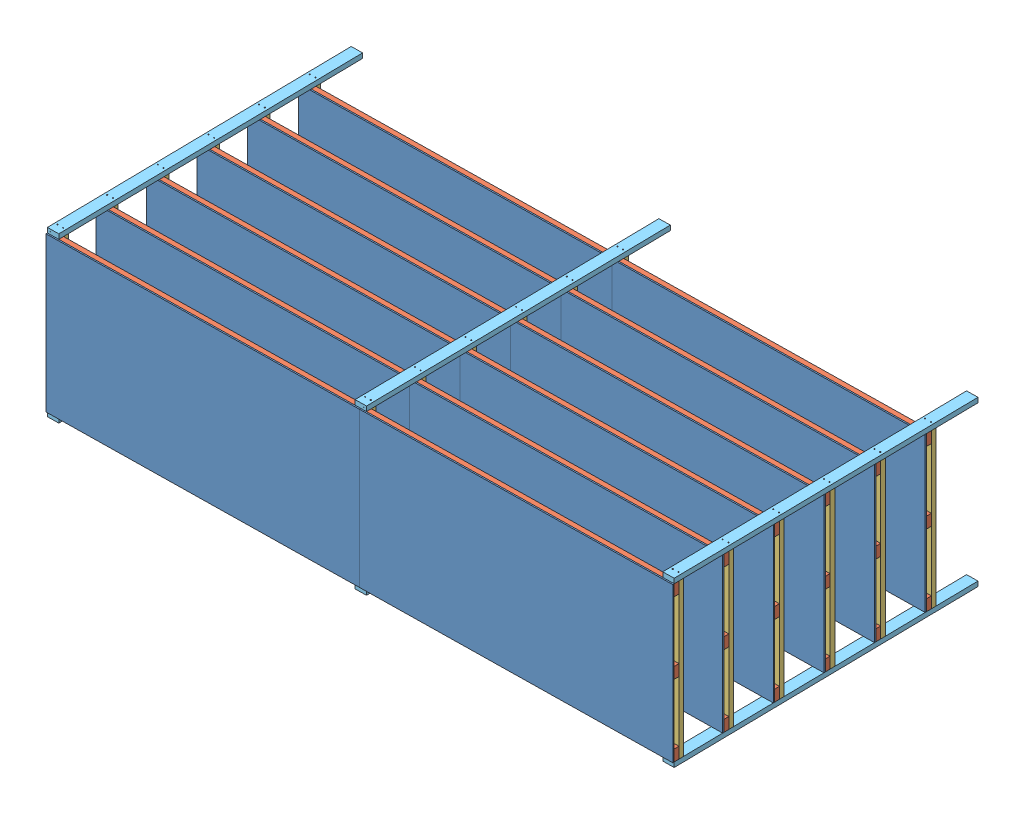
SolidWorks assembly Shelves, configuration Default. Lengths in mm.
Overall size (4914.37 1300.4 2525.2).
264 component instances, 5 part files, 8 mates.
Components (placement in the parent):
- Shelf-8: Shelf [Default] at (-1320.3436 -2276.2695 -924.1051) x (0 1 0) z (0.01558 0 0.999879) size (1219.2 4876.8 89.81)
  - Plywood_7-16X4ftX8ft-1: Plywood_7-16X4ftX8ft [Default] at (-1214.3269 -1248.9803 333.7822) size (1219.2 2438.4 11.11)
  - Plywood_7-16X4ftX8ft-2: Plywood_7-16X4ftX8ft [Default] at (-1214.3269 1189.4197 333.7822) size (1219.2 2438.4 11.11)
  - 2x4x16ft-4: 2x4x16ft [Default] at (-84.0269 -1248.9803 333.7822) x (1 0 0) z (0 1 0) size (88.9 38.1 4876.8)
  - 2x4x16ft-5: 2x4x16ft [Default] at (-649.1769 -1248.9803 333.7822) x (1 0 0) z (0 1 0) size (88.9 38.1 4876.8)
  - 2x4x16ft-6: 2x4x16ft [Default] at (-1214.3269 -1248.9803 333.7822) x (1 0 0) z (0 1 0) size (88.9 38.1 4876.8)
  - Fastened2x4x4ft-1: Fastened2x4x4ft [Default] at (-567.3467 -1138.8169 272.6519) x (0 1 0) z (-1 0 0) size (88.9 72.35 1219.2)
    - 2x4x4ft-1: 2x4x4ft [Default] at (-110.1634 -23.0303 -572.2198) size (88.9 38.1 1219.2)
    - DrywallScrew-1: DrywallScrew [Default] at (-65.7134 15.0697 624.7552) x (1 0 0) z (0 -1 0) size (6.35 6.35 72.35)
    - DrywallScrew-2: DrywallScrew [Default] at (-65.7134 15.0697 580.3052) x (1 0 0) z (0 -1 0) size (6.35 6.35 72.35)
    - DrywallScrew-3: DrywallScrew [Default] at (-65.7134 15.0697 59.6052) x (1 0 0) z (0 -1 0) size (6.35 6.35 72.35)
    - DrywallScrew-4: DrywallScrew [Default] at (-65.7134 15.0697 15.1552) x (1 0 0) z (0 -1 0) size (6.35 6.35 72.35)
    - DrywallScrew-5: DrywallScrew [Default] at (-65.7134 15.0697 -549.9948) x (1 0 0) z (0 -1 0) size (6.35 6.35 72.35)
    - DrywallScrew-6: DrywallScrew [Default] at (-65.7134 15.0697 -505.5448) x (1 0 0) z (0 -1 0) size (6.35 6.35 72.35)
  - Fastened2x4x4ft-2: Fastened2x4x4ft [Default] at (-567.3467 1255.1331 272.6519) x (0 1 0) z (-1 0 0) size (88.9 72.35 1219.2)
    - 2x4x4ft-1: 2x4x4ft [Default] at (-110.1634 -23.0303 -572.2198) size (88.9 38.1 1219.2)
    - DrywallScrew-1: DrywallScrew [Default] at (-65.7134 15.0697 624.7552) x (1 0 0) z (0 -1 0) size (6.35 6.35 72.35)
    - DrywallScrew-2: DrywallScrew [Default] at (-65.7134 15.0697 580.3052) x (1 0 0) z (0 -1 0) size (6.35 6.35 72.35)
    - DrywallScrew-3: DrywallScrew [Default] at (-65.7134 15.0697 59.6052) x (1 0 0) z (0 -1 0) size (6.35 6.35 72.35)
    - DrywallScrew-4: DrywallScrew [Default] at (-65.7134 15.0697 15.1552) x (1 0 0) z (0 -1 0) size (6.35 6.35 72.35)
    - DrywallScrew-5: DrywallScrew [Default] at (-65.7134 15.0697 -549.9948) x (1 0 0) z (0 -1 0) size (6.35 6.35 72.35)
    - DrywallScrew-6: DrywallScrew [Default] at (-65.7134 15.0697 -505.5448) x (1 0 0) z (0 -1 0) size (6.35 6.35 72.35)
  - Fastened2x4x4ft-3: Fastened2x4x4ft [Default] at (-642.1071 3517.6563 272.6519) x (0 -1 0) z (1 0 0) size (88.9 72.35 1219.2)
    - 2x4x4ft-1: 2x4x4ft [Default] at (-110.1634 -23.0303 -572.2198) size (88.9 38.1 1219.2)
    - DrywallScrew-1: DrywallScrew [Default] at (-65.7134 15.0697 624.7552) x (1 0 0) z (0 -1 0) size (6.35 6.35 72.35)
    - DrywallScrew-2: DrywallScrew [Default] at (-65.7134 15.0697 580.3052) x (1 0 0) z (0 -1 0) size (6.35 6.35 72.35)
    - DrywallScrew-3: DrywallScrew [Default] at (-65.7134 15.0697 59.6052) x (1 0 0) z (0 -1 0) size (6.35 6.35 72.35)
    - DrywallScrew-4: DrywallScrew [Default] at (-65.7134 15.0697 15.1552) x (1 0 0) z (0 -1 0) size (6.35 6.35 72.35)
    - DrywallScrew-5: DrywallScrew [Default] at (-65.7134 15.0697 -549.9948) x (1 0 0) z (0 -1 0) size (6.35 6.35 72.35)
    - DrywallScrew-6: DrywallScrew [Default] at (-65.7134 15.0697 -505.5448) x (1 0 0) z (0 -1 0) size (6.35 6.35 72.35)
- Fastened2x4x8ft-1: Fastened2x4x8ft [Default] at (199.4493 -2217.0742 10.0157) x (0.999879 0 -0.01558) z (0.01558 0 0.999879) size (88.9 72.35 2438.4)
  - 2x4x8ft-1: 2x4x8ft [Default] at (-344.9743 -54.3222 -1036.654) size (88.9 38.1 2438.4)
  - DrywallScrew-1: DrywallScrew [Default] at (-322.7493 -16.2222 1344.596) x (1 0 0) z (0 -1 0) size (6.35 6.35 72.35)
  - DrywallScrew-2: DrywallScrew [Default] at (-278.2993 -16.2222 1344.596) x (1 0 0) z (0 -1 0) size (6.35 6.35 72.35)
  - DrywallScrew-3: DrywallScrew [Default] at (-278.2993 -16.2222 944.546) x (1 0 0) z (0 -1 0) size (6.35 6.35 72.35)
  - DrywallScrew-4: DrywallScrew [Default] at (-322.7493 -16.2222 944.546) x (1 0 0) z (0 -1 0) size (6.35 6.35 72.35)
  - DrywallScrew-5: DrywallScrew [Default] at (-278.2993 -16.2222 538.146) x (1 0 0) z (0 -1 0) size (6.35 6.35 72.35)
  - DrywallScrew-6: DrywallScrew [Default] at (-278.2993 -16.2222 131.746) x (1 0 0) z (0 -1 0) size (6.35 6.35 72.35)
  - DrywallScrew-7: DrywallScrew [Default] at (-278.2993 -16.2222 -274.654) x (1 0 0) z (0 -1 0) size (6.35 6.35 72.35)
  - DrywallScrew-8: DrywallScrew [Default] at (-278.2993 -16.2222 -681.054) x (1 0 0) z (0 -1 0) size (6.35 6.35 72.35)
  - DrywallScrew-9: DrywallScrew [Default] at (-322.7493 -16.2222 538.146) x (1 0 0) z (0 -1 0) size (6.35 6.35 72.35)
  - DrywallScrew-10: DrywallScrew [Default] at (-322.7493 -16.2222 131.746) x (1 0 0) z (0 -1 0) size (6.35 6.35 72.35)
  - DrywallScrew-11: DrywallScrew [Default] at (-322.7493 -16.2222 -274.654) x (1 0 0) z (0 -1 0) size (6.35 6.35 72.35)
  - DrywallScrew-12: DrywallScrew [Default] at (-322.7493 -16.2222 -681.054) x (1 0 0) z (0 -1 0) size (6.35 6.35 72.35)
- Fastened2x4x8ft-2: Fastened2x4x8ft [Default] at (-4587.8696 -2217.0742 84.6123) x (0.999879 0 -0.01558) z (0.01558 0 0.999879) size (88.9 72.35 2438.4)
  - 2x4x8ft-1: 2x4x8ft [Default] at (-344.9743 -54.3222 -1036.654) size (88.9 38.1 2438.4)
  - DrywallScrew-1: DrywallScrew [Default] at (-322.7493 -16.2222 1344.596) x (1 0 0) z (0 -1 0) size (6.35 6.35 72.35)
  - DrywallScrew-2: DrywallScrew [Default] at (-278.2993 -16.2222 1344.596) x (1 0 0) z (0 -1 0) size (6.35 6.35 72.35)
  - DrywallScrew-3: DrywallScrew [Default] at (-278.2993 -16.2222 944.546) x (1 0 0) z (0 -1 0) size (6.35 6.35 72.35)
  - DrywallScrew-4: DrywallScrew [Default] at (-322.7493 -16.2222 944.546) x (1 0 0) z (0 -1 0) size (6.35 6.35 72.35)
  - DrywallScrew-5: DrywallScrew [Default] at (-278.2993 -16.2222 538.146) x (1 0 0) z (0 -1 0) size (6.35 6.35 72.35)
  - DrywallScrew-6: DrywallScrew [Default] at (-278.2993 -16.2222 131.746) x (1 0 0) z (0 -1 0) size (6.35 6.35 72.35)
  - DrywallScrew-7: DrywallScrew [Default] at (-278.2993 -16.2222 -274.654) x (1 0 0) z (0 -1 0) size (6.35 6.35 72.35)
  - DrywallScrew-8: DrywallScrew [Default] at (-278.2993 -16.2222 -681.054) x (1 0 0) z (0 -1 0) size (6.35 6.35 72.35)
  - DrywallScrew-9: DrywallScrew [Default] at (-322.7493 -16.2222 538.146) x (1 0 0) z (0 -1 0) size (6.35 6.35 72.35)
  - DrywallScrew-10: DrywallScrew [Default] at (-322.7493 -16.2222 131.746) x (1 0 0) z (0 -1 0) size (6.35 6.35 72.35)
  - DrywallScrew-11: DrywallScrew [Default] at (-322.7493 -16.2222 -274.654) x (1 0 0) z (0 -1 0) size (6.35 6.35 72.35)
  - DrywallScrew-12: DrywallScrew [Default] at (-322.7493 -16.2222 -681.054) x (1 0 0) z (0 -1 0) size (6.35 6.35 72.35)
- Fastened2x4x8ft-3: Fastened2x4x8ft [Default] at (-2194.2102 -2217.0742 47.314) x (0.999879 0 -0.01558) z (0.01558 0 0.999879) size (88.9 72.35 2438.4)
  - 2x4x8ft-1: 2x4x8ft [Default] at (-344.9743 -54.3222 -1036.654) size (88.9 38.1 2438.4)
  - DrywallScrew-1: DrywallScrew [Default] at (-322.7493 -16.2222 1344.596) x (1 0 0) z (0 -1 0) size (6.35 6.35 72.35)
  - DrywallScrew-2: DrywallScrew [Default] at (-278.2993 -16.2222 1344.596) x (1 0 0) z (0 -1 0) size (6.35 6.35 72.35)
  - DrywallScrew-3: DrywallScrew [Default] at (-278.2993 -16.2222 944.546) x (1 0 0) z (0 -1 0) size (6.35 6.35 72.35)
  - DrywallScrew-4: DrywallScrew [Default] at (-322.7493 -16.2222 944.546) x (1 0 0) z (0 -1 0) size (6.35 6.35 72.35)
  - DrywallScrew-5: DrywallScrew [Default] at (-278.2993 -16.2222 538.146) x (1 0 0) z (0 -1 0) size (6.35 6.35 72.35)
  - DrywallScrew-6: DrywallScrew [Default] at (-278.2993 -16.2222 131.746) x (1 0 0) z (0 -1 0) size (6.35 6.35 72.35)
  - DrywallScrew-7: DrywallScrew [Default] at (-278.2993 -16.2222 -274.654) x (1 0 0) z (0 -1 0) size (6.35 6.35 72.35)
  - DrywallScrew-8: DrywallScrew [Default] at (-278.2993 -16.2222 -681.054) x (1 0 0) z (0 -1 0) size (6.35 6.35 72.35)
  - DrywallScrew-9: DrywallScrew [Default] at (-322.7493 -16.2222 538.146) x (1 0 0) z (0 -1 0) size (6.35 6.35 72.35)
  - DrywallScrew-10: DrywallScrew [Default] at (-322.7493 -16.2222 131.746) x (1 0 0) z (0 -1 0) size (6.35 6.35 72.35)
  - DrywallScrew-11: DrywallScrew [Default] at (-322.7493 -16.2222 -274.654) x (1 0 0) z (0 -1 0) size (6.35 6.35 72.35)
  - DrywallScrew-12: DrywallScrew [Default] at (-322.7493 -16.2222 -681.054) x (1 0 0) z (0 -1 0) size (6.35 6.35 72.35)
- Fastened2x4x8ft-4: Fastened2x4x8ft [Default] at (-2795.1858 -3544.9185 56.6785) x (-0.999879 0 0.01558) z (0.01558 0 0.999879) size (88.9 72.35 2438.4)
  - 2x4x8ft-1: 2x4x8ft [Default] at (-344.9743 -54.3222 -1036.654) size (88.9 38.1 2438.4)
  - DrywallScrew-1: DrywallScrew [Default] at (-322.7493 -16.2222 1344.596) x (1 0 0) z (0 -1 0) size (6.35 6.35 72.35)
  - DrywallScrew-2: DrywallScrew [Default] at (-278.2993 -16.2222 1344.596) x (1 0 0) z (0 -1 0) size (6.35 6.35 72.35)
  - DrywallScrew-3: DrywallScrew [Default] at (-278.2993 -16.2222 944.546) x (1 0 0) z (0 -1 0) size (6.35 6.35 72.35)
  - DrywallScrew-4: DrywallScrew [Default] at (-322.7493 -16.2222 944.546) x (1 0 0) z (0 -1 0) size (6.35 6.35 72.35)
  - DrywallScrew-5: DrywallScrew [Default] at (-278.2993 -16.2222 538.146) x (1 0 0) z (0 -1 0) size (6.35 6.35 72.35)
  - DrywallScrew-6: DrywallScrew [Default] at (-278.2993 -16.2222 131.746) x (1 0 0) z (0 -1 0) size (6.35 6.35 72.35)
  - DrywallScrew-7: DrywallScrew [Default] at (-278.2993 -16.2222 -274.654) x (1 0 0) z (0 -1 0) size (6.35 6.35 72.35)
  - DrywallScrew-8: DrywallScrew [Default] at (-278.2993 -16.2222 -681.054) x (1 0 0) z (0 -1 0) size (6.35 6.35 72.35)
  - DrywallScrew-9: DrywallScrew [Default] at (-322.7493 -16.2222 538.146) x (1 0 0) z (0 -1 0) size (6.35 6.35 72.35)
  - DrywallScrew-10: DrywallScrew [Default] at (-322.7493 -16.2222 131.746) x (1 0 0) z (0 -1 0) size (6.35 6.35 72.35)
  - DrywallScrew-11: DrywallScrew [Default] at (-322.7493 -16.2222 -274.654) x (1 0 0) z (0 -1 0) size (6.35 6.35 72.35)
  - DrywallScrew-12: DrywallScrew [Default] at (-322.7493 -16.2222 -681.054) x (1 0 0) z (0 -1 0) size (6.35 6.35 72.35)
- Fastened2x4x8ft-5: Fastened2x4x8ft [Default] at (-5188.8453 -3544.9185 93.9768) x (-0.999879 0 0.01558) z (0.01558 0 0.999879) size (88.9 72.35 2438.4)
  - 2x4x8ft-1: 2x4x8ft [Default] at (-344.9743 -54.3222 -1036.654) size (88.9 38.1 2438.4)
  - DrywallScrew-1: DrywallScrew [Default] at (-322.7493 -16.2222 1344.596) x (1 0 0) z (0 -1 0) size (6.35 6.35 72.35)
  - DrywallScrew-2: DrywallScrew [Default] at (-278.2993 -16.2222 1344.596) x (1 0 0) z (0 -1 0) size (6.35 6.35 72.35)
  - DrywallScrew-3: DrywallScrew [Default] at (-278.2993 -16.2222 944.546) x (1 0 0) z (0 -1 0) size (6.35 6.35 72.35)
  - DrywallScrew-4: DrywallScrew [Default] at (-322.7493 -16.2222 944.546) x (1 0 0) z (0 -1 0) size (6.35 6.35 72.35)
  - DrywallScrew-5: DrywallScrew [Default] at (-278.2993 -16.2222 538.146) x (1 0 0) z (0 -1 0) size (6.35 6.35 72.35)
  - DrywallScrew-6: DrywallScrew [Default] at (-278.2993 -16.2222 131.746) x (1 0 0) z (0 -1 0) size (6.35 6.35 72.35)
  - DrywallScrew-7: DrywallScrew [Default] at (-278.2993 -16.2222 -274.654) x (1 0 0) z (0 -1 0) size (6.35 6.35 72.35)
  - DrywallScrew-8: DrywallScrew [Default] at (-278.2993 -16.2222 -681.054) x (1 0 0) z (0 -1 0) size (6.35 6.35 72.35)
  - DrywallScrew-9: DrywallScrew [Default] at (-322.7493 -16.2222 538.146) x (1 0 0) z (0 -1 0) size (6.35 6.35 72.35)
  - DrywallScrew-10: DrywallScrew [Default] at (-322.7493 -16.2222 131.746) x (1 0 0) z (0 -1 0) size (6.35 6.35 72.35)
  - DrywallScrew-11: DrywallScrew [Default] at (-322.7493 -16.2222 -274.654) x (1 0 0) z (0 -1 0) size (6.35 6.35 72.35)
  - DrywallScrew-12: DrywallScrew [Default] at (-322.7493 -16.2222 -681.054) x (1 0 0) z (0 -1 0) size (6.35 6.35 72.35)
- Fastened2x4x8ft-6: Fastened2x4x8ft [Default] at (-401.5264 -3544.9185 19.3802) x (-0.999879 0 0.01558) z (0.01558 0 0.999879) size (88.9 72.35 2438.4)
  - 2x4x8ft-1: 2x4x8ft [Default] at (-344.9743 -54.3222 -1036.654) size (88.9 38.1 2438.4)
  - DrywallScrew-1: DrywallScrew [Default] at (-322.7493 -16.2222 1344.596) x (1 0 0) z (0 -1 0) size (6.35 6.35 72.35)
  - DrywallScrew-2: DrywallScrew [Default] at (-278.2993 -16.2222 1344.596) x (1 0 0) z (0 -1 0) size (6.35 6.35 72.35)
  - DrywallScrew-3: DrywallScrew [Default] at (-278.2993 -16.2222 944.546) x (1 0 0) z (0 -1 0) size (6.35 6.35 72.35)
  - DrywallScrew-4: DrywallScrew [Default] at (-322.7493 -16.2222 944.546) x (1 0 0) z (0 -1 0) size (6.35 6.35 72.35)
  - DrywallScrew-5: DrywallScrew [Default] at (-278.2993 -16.2222 538.146) x (1 0 0) z (0 -1 0) size (6.35 6.35 72.35)
  - DrywallScrew-6: DrywallScrew [Default] at (-278.2993 -16.2222 131.746) x (1 0 0) z (0 -1 0) size (6.35 6.35 72.35)
  - DrywallScrew-7: DrywallScrew [Default] at (-278.2993 -16.2222 -274.654) x (1 0 0) z (0 -1 0) size (6.35 6.35 72.35)
  - DrywallScrew-8: DrywallScrew [Default] at (-278.2993 -16.2222 -681.054) x (1 0 0) z (0 -1 0) size (6.35 6.35 72.35)
  - DrywallScrew-9: DrywallScrew [Default] at (-322.7493 -16.2222 538.146) x (1 0 0) z (0 -1 0) size (6.35 6.35 72.35)
  - DrywallScrew-10: DrywallScrew [Default] at (-322.7493 -16.2222 131.746) x (1 0 0) z (0 -1 0) size (6.35 6.35 72.35)
  - DrywallScrew-11: DrywallScrew [Default] at (-322.7493 -16.2222 -274.654) x (1 0 0) z (0 -1 0) size (6.35 6.35 72.35)
  - DrywallScrew-12: DrywallScrew [Default] at (-322.7493 -16.2222 -681.054) x (1 0 0) z (0 -1 0) size (6.35 6.35 72.35)
- Shelf-9: Shelf [Default] at (-1314.0118 -2276.2695 -517.7545) x (0 1 0) z (0.01558 0 0.999879) size (1219.2 4876.8 89.81)
  - Plywood_7-16X4ftX8ft-1: Plywood_7-16X4ftX8ft [Default] at (-1214.3269 -1248.9803 333.7822) size (1219.2 2438.4 11.11)
  - Plywood_7-16X4ftX8ft-2: Plywood_7-16X4ftX8ft [Default] at (-1214.3269 1189.4197 333.7822) size (1219.2 2438.4 11.11)
  - 2x4x16ft-4: 2x4x16ft [Default] at (-84.0269 -1248.9803 333.7822) x (1 0 0) z (0 1 0) size (88.9 38.1 4876.8)
  - 2x4x16ft-5: 2x4x16ft [Default] at (-649.1769 -1248.9803 333.7822) x (1 0 0) z (0 1 0) size (88.9 38.1 4876.8)
  - 2x4x16ft-6: 2x4x16ft [Default] at (-1214.3269 -1248.9803 333.7822) x (1 0 0) z (0 1 0) size (88.9 38.1 4876.8)
  - Fastened2x4x4ft-1: Fastened2x4x4ft [Default] at (-567.3467 -1138.8169 272.6519) x (0 1 0) z (-1 0 0) size (88.9 72.35 1219.2)
    - 2x4x4ft-1: 2x4x4ft [Default] at (-110.1634 -23.0303 -572.2198) size (88.9 38.1 1219.2)
    - DrywallScrew-1: DrywallScrew [Default] at (-65.7134 15.0697 624.7552) x (1 0 0) z (0 -1 0) size (6.35 6.35 72.35)
    - DrywallScrew-2: DrywallScrew [Default] at (-65.7134 15.0697 580.3052) x (1 0 0) z (0 -1 0) size (6.35 6.35 72.35)
    - DrywallScrew-3: DrywallScrew [Default] at (-65.7134 15.0697 59.6052) x (1 0 0) z (0 -1 0) size (6.35 6.35 72.35)
    - DrywallScrew-4: DrywallScrew [Default] at (-65.7134 15.0697 15.1552) x (1 0 0) z (0 -1 0) size (6.35 6.35 72.35)
    - DrywallScrew-5: DrywallScrew [Default] at (-65.7134 15.0697 -549.9948) x (1 0 0) z (0 -1 0) size (6.35 6.35 72.35)
    - DrywallScrew-6: DrywallScrew [Default] at (-65.7134 15.0697 -505.5448) x (1 0 0) z (0 -1 0) size (6.35 6.35 72.35)
  - Fastened2x4x4ft-2: Fastened2x4x4ft [Default] at (-567.3467 1255.1331 272.6519) x (0 1 0) z (-1 0 0) size (88.9 72.35 1219.2)
    - 2x4x4ft-1: 2x4x4ft [Default] at (-110.1634 -23.0303 -572.2198) size (88.9 38.1 1219.2)
    - DrywallScrew-1: DrywallScrew [Default] at (-65.7134 15.0697 624.7552) x (1 0 0) z (0 -1 0) size (6.35 6.35 72.35)
    - DrywallScrew-2: DrywallScrew [Default] at (-65.7134 15.0697 580.3052) x (1 0 0) z (0 -1 0) size (6.35 6.35 72.35)
    - DrywallScrew-3: DrywallScrew [Default] at (-65.7134 15.0697 59.6052) x (1 0 0) z (0 -1 0) size (6.35 6.35 72.35)
    - DrywallScrew-4: DrywallScrew [Default] at (-65.7134 15.0697 15.1552) x (1 0 0) z (0 -1 0) size (6.35 6.35 72.35)
    - DrywallScrew-5: DrywallScrew [Default] at (-65.7134 15.0697 -549.9948) x (1 0 0) z (0 -1 0) size (6.35 6.35 72.35)
    - DrywallScrew-6: DrywallScrew [Default] at (-65.7134 15.0697 -505.5448) x (1 0 0) z (0 -1 0) size (6.35 6.35 72.35)
  - Fastened2x4x4ft-3: Fastened2x4x4ft [Default] at (-642.1071 3517.6563 272.6519) x (0 -1 0) z (1 0 0) size (88.9 72.35 1219.2)
    - 2x4x4ft-1: 2x4x4ft [Default] at (-110.1634 -23.0303 -572.2198) size (88.9 38.1 1219.2)
    - DrywallScrew-1: DrywallScrew [Default] at (-65.7134 15.0697 624.7552) x (1 0 0) z (0 -1 0) size (6.35 6.35 72.35)
    - DrywallScrew-2: DrywallScrew [Default] at (-65.7134 15.0697 580.3052) x (1 0 0) z (0 -1 0) size (6.35 6.35 72.35)
    - DrywallScrew-3: DrywallScrew [Default] at (-65.7134 15.0697 59.6052) x (1 0 0) z (0 -1 0) size (6.35 6.35 72.35)
    - DrywallScrew-4: DrywallScrew [Default] at (-65.7134 15.0697 15.1552) x (1 0 0) z (0 -1 0) size (6.35 6.35 72.35)
    - DrywallScrew-5: DrywallScrew [Default] at (-65.7134 15.0697 -549.9948) x (1 0 0) z (0 -1 0) size (6.35 6.35 72.35)
    - DrywallScrew-6: DrywallScrew [Default] at (-65.7134 15.0697 -505.5448) x (1 0 0) z (0 -1 0) size (6.35 6.35 72.35)
- Shelf-10: Shelf [Default] at (-1307.68 -2276.2695 -111.4038) x (0 1 0) z (0.01558 0 0.999879) size (1219.2 4876.8 89.81)
  - Plywood_7-16X4ftX8ft-1: Plywood_7-16X4ftX8ft [Default] at (-1214.3269 -1248.9803 333.7822) size (1219.2 2438.4 11.11)
  - Plywood_7-16X4ftX8ft-2: Plywood_7-16X4ftX8ft [Default] at (-1214.3269 1189.4197 333.7822) size (1219.2 2438.4 11.11)
  - 2x4x16ft-4: 2x4x16ft [Default] at (-84.0269 -1248.9803 333.7822) x (1 0 0) z (0 1 0) size (88.9 38.1 4876.8)
  - 2x4x16ft-5: 2x4x16ft [Default] at (-649.1769 -1248.9803 333.7822) x (1 0 0) z (0 1 0) size (88.9 38.1 4876.8)
  - 2x4x16ft-6: 2x4x16ft [Default] at (-1214.3269 -1248.9803 333.7822) x (1 0 0) z (0 1 0) size (88.9 38.1 4876.8)
  - Fastened2x4x4ft-1: Fastened2x4x4ft [Default] at (-567.3467 -1138.8169 272.6519) x (0 1 0) z (-1 0 0) size (88.9 72.35 1219.2)
    - 2x4x4ft-1: 2x4x4ft [Default] at (-110.1634 -23.0303 -572.2198) size (88.9 38.1 1219.2)
    - DrywallScrew-1: DrywallScrew [Default] at (-65.7134 15.0697 624.7552) x (1 0 0) z (0 -1 0) size (6.35 6.35 72.35)
    - DrywallScrew-2: DrywallScrew [Default] at (-65.7134 15.0697 580.3052) x (1 0 0) z (0 -1 0) size (6.35 6.35 72.35)
    - DrywallScrew-3: DrywallScrew [Default] at (-65.7134 15.0697 59.6052) x (1 0 0) z (0 -1 0) size (6.35 6.35 72.35)
    - DrywallScrew-4: DrywallScrew [Default] at (-65.7134 15.0697 15.1552) x (1 0 0) z (0 -1 0) size (6.35 6.35 72.35)
    - DrywallScrew-5: DrywallScrew [Default] at (-65.7134 15.0697 -549.9948) x (1 0 0) z (0 -1 0) size (6.35 6.35 72.35)
    - DrywallScrew-6: DrywallScrew [Default] at (-65.7134 15.0697 -505.5448) x (1 0 0) z (0 -1 0) size (6.35 6.35 72.35)
  - Fastened2x4x4ft-2: Fastened2x4x4ft [Default] at (-567.3467 1255.1331 272.6519) x (0 1 0) z (-1 0 0) size (88.9 72.35 1219.2)
    - 2x4x4ft-1: 2x4x4ft [Default] at (-110.1634 -23.0303 -572.2198) size (88.9 38.1 1219.2)
    - DrywallScrew-1: DrywallScrew [Default] at (-65.7134 15.0697 624.7552) x (1 0 0) z (0 -1 0) size (6.35 6.35 72.35)
    - DrywallScrew-2: DrywallScrew [Default] at (-65.7134 15.0697 580.3052) x (1 0 0) z (0 -1 0) size (6.35 6.35 72.35)
    - DrywallScrew-3: DrywallScrew [Default] at (-65.7134 15.0697 59.6052) x (1 0 0) z (0 -1 0) size (6.35 6.35 72.35)
    - DrywallScrew-4: DrywallScrew [Default] at (-65.7134 15.0697 15.1552) x (1 0 0) z (0 -1 0) size (6.35 6.35 72.35)
    - DrywallScrew-5: DrywallScrew [Default] at (-65.7134 15.0697 -549.9948) x (1 0 0) z (0 -1 0) size (6.35 6.35 72.35)
    - DrywallScrew-6: DrywallScrew [Default] at (-65.7134 15.0697 -505.5448) x (1 0 0) z (0 -1 0) size (6.35 6.35 72.35)
  - Fastened2x4x4ft-3: Fastened2x4x4ft [Default] at (-642.1071 3517.6563 272.6519) x (0 -1 0) z (1 0 0) size (88.9 72.35 1219.2)
    - 2x4x4ft-1: 2x4x4ft [Default] at (-110.1634 -23.0303 -572.2198) size (88.9 38.1 1219.2)
    - DrywallScrew-1: DrywallScrew [Default] at (-65.7134 15.0697 624.7552) x (1 0 0) z (0 -1 0) size (6.35 6.35 72.35)
    - DrywallScrew-2: DrywallScrew [Default] at (-65.7134 15.0697 580.3052) x (1 0 0) z (0 -1 0) size (6.35 6.35 72.35)
    - DrywallScrew-3: DrywallScrew [Default] at (-65.7134 15.0697 59.6052) x (1 0 0) z (0 -1 0) size (6.35 6.35 72.35)
    - DrywallScrew-4: DrywallScrew [Default] at (-65.7134 15.0697 15.1552) x (1 0 0) z (0 -1 0) size (6.35 6.35 72.35)
    - DrywallScrew-5: DrywallScrew [Default] at (-65.7134 15.0697 -549.9948) x (1 0 0) z (0 -1 0) size (6.35 6.35 72.35)
    - DrywallScrew-6: DrywallScrew [Default] at (-65.7134 15.0697 -505.5448) x (1 0 0) z (0 -1 0) size (6.35 6.35 72.35)
- Shelf-11: Shelf [Default] at (-1301.3482 -2276.2695 294.9469) x (0 1 0) z (0.01558 0 0.999879) size (1219.2 4876.8 89.81)
  - Plywood_7-16X4ftX8ft-1: Plywood_7-16X4ftX8ft [Default] at (-1214.3269 -1248.9803 333.7822) size (1219.2 2438.4 11.11)
  - Plywood_7-16X4ftX8ft-2: Plywood_7-16X4ftX8ft [Default] at (-1214.3269 1189.4197 333.7822) size (1219.2 2438.4 11.11)
  - 2x4x16ft-4: 2x4x16ft [Default] at (-84.0269 -1248.9803 333.7822) x (1 0 0) z (0 1 0) size (88.9 38.1 4876.8)
  - 2x4x16ft-5: 2x4x16ft [Default] at (-649.1769 -1248.9803 333.7822) x (1 0 0) z (0 1 0) size (88.9 38.1 4876.8)
  - 2x4x16ft-6: 2x4x16ft [Default] at (-1214.3269 -1248.9803 333.7822) x (1 0 0) z (0 1 0) size (88.9 38.1 4876.8)
  - Fastened2x4x4ft-1: Fastened2x4x4ft [Default] at (-567.3467 -1138.8169 272.6519) x (0 1 0) z (-1 0 0) size (88.9 72.35 1219.2)
    - 2x4x4ft-1: 2x4x4ft [Default] at (-110.1634 -23.0303 -572.2198) size (88.9 38.1 1219.2)
    - DrywallScrew-1: DrywallScrew [Default] at (-65.7134 15.0697 624.7552) x (1 0 0) z (0 -1 0) size (6.35 6.35 72.35)
    - DrywallScrew-2: DrywallScrew [Default] at (-65.7134 15.0697 580.3052) x (1 0 0) z (0 -1 0) size (6.35 6.35 72.35)
    - DrywallScrew-3: DrywallScrew [Default] at (-65.7134 15.0697 59.6052) x (1 0 0) z (0 -1 0) size (6.35 6.35 72.35)
    - DrywallScrew-4: DrywallScrew [Default] at (-65.7134 15.0697 15.1552) x (1 0 0) z (0 -1 0) size (6.35 6.35 72.35)
    - DrywallScrew-5: DrywallScrew [Default] at (-65.7134 15.0697 -549.9948) x (1 0 0) z (0 -1 0) size (6.35 6.35 72.35)
    - DrywallScrew-6: DrywallScrew [Default] at (-65.7134 15.0697 -505.5448) x (1 0 0) z (0 -1 0) size (6.35 6.35 72.35)
  - Fastened2x4x4ft-2: Fastened2x4x4ft [Default] at (-567.3467 1255.1331 272.6519) x (0 1 0) z (-1 0 0) size (88.9 72.35 1219.2)
    - 2x4x4ft-1: 2x4x4ft [Default] at (-110.1634 -23.0303 -572.2198) size (88.9 38.1 1219.2)
    - DrywallScrew-1: DrywallScrew [Default] at (-65.7134 15.0697 624.7552) x (1 0 0) z (0 -1 0) size (6.35 6.35 72.35)
    - DrywallScrew-2: DrywallScrew [Default] at (-65.7134 15.0697 580.3052) x (1 0 0) z (0 -1 0) size (6.35 6.35 72.35)
    - DrywallScrew-3: DrywallScrew [Default] at (-65.7134 15.0697 59.6052) x (1 0 0) z (0 -1 0) size (6.35 6.35 72.35)
    - DrywallScrew-4: DrywallScrew [Default] at (-65.7134 15.0697 15.1552) x (1 0 0) z (0 -1 0) size (6.35 6.35 72.35)
    - DrywallScrew-5: DrywallScrew [Default] at (-65.7134 15.0697 -549.9948) x (1 0 0) z (0 -1 0) size (6.35 6.35 72.35)
    - DrywallScrew-6: DrywallScrew [Default] at (-65.7134 15.0697 -505.5448) x (1 0 0) z (0 -1 0) size (6.35 6.35 72.35)
  - Fastened2x4x4ft-3: Fastened2x4x4ft [Default] at (-642.1071 3517.6563 272.6519) x (0 -1 0) z (1 0 0) size (88.9 72.35 1219.2)
    - 2x4x4ft-1: 2x4x4ft [Default] at (-110.1634 -23.0303 -572.2198) size (88.9 38.1 1219.2)
    - DrywallScrew-1: DrywallScrew [Default] at (-65.7134 15.0697 624.7552) x (1 0 0) z (0 -1 0) size (6.35 6.35 72.35)
    - DrywallScrew-2: DrywallScrew [Default] at (-65.7134 15.0697 580.3052) x (1 0 0) z (0 -1 0) size (6.35 6.35 72.35)
    - DrywallScrew-3: DrywallScrew [Default] at (-65.7134 15.0697 59.6052) x (1 0 0) z (0 -1 0) size (6.35 6.35 72.35)
    - DrywallScrew-4: DrywallScrew [Default] at (-65.7134 15.0697 15.1552) x (1 0 0) z (0 -1 0) size (6.35 6.35 72.35)
    - DrywallScrew-5: DrywallScrew [Default] at (-65.7134 15.0697 -549.9948) x (1 0 0) z (0 -1 0) size (6.35 6.35 72.35)
    - DrywallScrew-6: DrywallScrew [Default] at (-65.7134 15.0697 -505.5448) x (1 0 0) z (0 -1 0) size (6.35 6.35 72.35)
- Shelf-12: Shelf [Default] at (-1295.0164 -2276.2695 701.2976) x (0 1 0) z (0.01558 0 0.999879) size (1219.2 4876.8 89.81)
  - Plywood_7-16X4ftX8ft-1: Plywood_7-16X4ftX8ft [Default] at (-1214.3269 -1248.9803 333.7822) size (1219.2 2438.4 11.11)
  - Plywood_7-16X4ftX8ft-2: Plywood_7-16X4ftX8ft [Default] at (-1214.3269 1189.4197 333.7822) size (1219.2 2438.4 11.11)
  - 2x4x16ft-4: 2x4x16ft [Default] at (-84.0269 -1248.9803 333.7822) x (1 0 0) z (0 1 0) size (88.9 38.1 4876.8)
  - 2x4x16ft-5: 2x4x16ft [Default] at (-649.1769 -1248.9803 333.7822) x (1 0 0) z (0 1 0) size (88.9 38.1 4876.8)
  - 2x4x16ft-6: 2x4x16ft [Default] at (-1214.3269 -1248.9803 333.7822) x (1 0 0) z (0 1 0) size (88.9 38.1 4876.8)
  - Fastened2x4x4ft-1: Fastened2x4x4ft [Default] at (-567.3467 -1138.8169 272.6519) x (0 1 0) z (-1 0 0) size (88.9 72.35 1219.2)
    - 2x4x4ft-1: 2x4x4ft [Default] at (-110.1634 -23.0303 -572.2198) size (88.9 38.1 1219.2)
    - DrywallScrew-1: DrywallScrew [Default] at (-65.7134 15.0697 624.7552) x (1 0 0) z (0 -1 0) size (6.35 6.35 72.35)
    - DrywallScrew-2: DrywallScrew [Default] at (-65.7134 15.0697 580.3052) x (1 0 0) z (0 -1 0) size (6.35 6.35 72.35)
    - DrywallScrew-3: DrywallScrew [Default] at (-65.7134 15.0697 59.6052) x (1 0 0) z (0 -1 0) size (6.35 6.35 72.35)
    - DrywallScrew-4: DrywallScrew [Default] at (-65.7134 15.0697 15.1552) x (1 0 0) z (0 -1 0) size (6.35 6.35 72.35)
    - DrywallScrew-5: DrywallScrew [Default] at (-65.7134 15.0697 -549.9948) x (1 0 0) z (0 -1 0) size (6.35 6.35 72.35)
    - DrywallScrew-6: DrywallScrew [Default] at (-65.7134 15.0697 -505.5448) x (1 0 0) z (0 -1 0) size (6.35 6.35 72.35)
  - Fastened2x4x4ft-2: Fastened2x4x4ft [Default] at (-567.3467 1255.1331 272.6519) x (0 1 0) z (-1 0 0) size (88.9 72.35 1219.2)
    - 2x4x4ft-1: 2x4x4ft [Default] at (-110.1634 -23.0303 -572.2198) size (88.9 38.1 1219.2)
    - DrywallScrew-1: DrywallScrew [Default] at (-65.7134 15.0697 624.7552) x (1 0 0) z (0 -1 0) size (6.35 6.35 72.35)
    - DrywallScrew-2: DrywallScrew [Default] at (-65.7134 15.0697 580.3052) x (1 0 0) z (0 -1 0) size (6.35 6.35 72.35)
    - DrywallScrew-3: DrywallScrew [Default] at (-65.7134 15.0697 59.6052) x (1 0 0) z (0 -1 0) size (6.35 6.35 72.35)
    - DrywallScrew-4: DrywallScrew [Default] at (-65.7134 15.0697 15.1552) x (1 0 0) z (0 -1 0) size (6.35 6.35 72.35)
    - DrywallScrew-5: DrywallScrew [Default] at (-65.7134 15.0697 -549.9948) x (1 0 0) z (0 -1 0) size (6.35 6.35 72.35)
    - DrywallScrew-6: DrywallScrew [Default] at (-65.7134 15.0697 -505.5448) x (1 0 0) z (0 -1 0) size (6.35 6.35 72.35)
  - Fastened2x4x4ft-3: Fastened2x4x4ft [Default] at (-642.1071 3517.6563 272.6519) x (0 -1 0) z (1 0 0) size (88.9 72.35 1219.2)
    - 2x4x4ft-1: 2x4x4ft [Default] at (-110.1634 -23.0303 -572.2198) size (88.9 38.1 1219.2)
    - DrywallScrew-1: DrywallScrew [Default] at (-65.7134 15.0697 624.7552) x (1 0 0) z (0 -1 0) size (6.35 6.35 72.35)
    - DrywallScrew-2: DrywallScrew [Default] at (-65.7134 15.0697 580.3052) x (1 0 0) z (0 -1 0) size (6.35 6.35 72.35)
    - DrywallScrew-3: DrywallScrew [Default] at (-65.7134 15.0697 59.6052) x (1 0 0) z (0 -1 0) size (6.35 6.35 72.35)
    - DrywallScrew-4: DrywallScrew [Default] at (-65.7134 15.0697 15.1552) x (1 0 0) z (0 -1 0) size (6.35 6.35 72.35)
    - DrywallScrew-5: DrywallScrew [Default] at (-65.7134 15.0697 -549.9948) x (1 0 0) z (0 -1 0) size (6.35 6.35 72.35)
    - DrywallScrew-6: DrywallScrew [Default] at (-65.7134 15.0697 -505.5448) x (1 0 0) z (0 -1 0) size (6.35 6.35 72.35)
- Shelf-13: Shelf [Default] at (-1288.7835 -2276.2695 1101.299) x (0 1 0) z (0.01558 0 0.999879) size (1219.2 4876.8 89.81)
  - Plywood_7-16X4ftX8ft-1: Plywood_7-16X4ftX8ft [Default] at (-1214.3269 -1248.9803 333.7822) size (1219.2 2438.4 11.11)
  - Plywood_7-16X4ftX8ft-2: Plywood_7-16X4ftX8ft [Default] at (-1214.3269 1189.4197 333.7822) size (1219.2 2438.4 11.11)
  - 2x4x16ft-4: 2x4x16ft [Default] at (-84.0269 -1248.9803 333.7822) x (1 0 0) z (0 1 0) size (88.9 38.1 4876.8)
  - 2x4x16ft-5: 2x4x16ft [Default] at (-649.1769 -1248.9803 333.7822) x (1 0 0) z (0 1 0) size (88.9 38.1 4876.8)
  - 2x4x16ft-6: 2x4x16ft [Default] at (-1214.3269 -1248.9803 333.7822) x (1 0 0) z (0 1 0) size (88.9 38.1 4876.8)
  - Fastened2x4x4ft-1: Fastened2x4x4ft [Default] at (-567.3467 -1138.8169 272.6519) x (0 1 0) z (-1 0 0) size (88.9 72.35 1219.2)
    - 2x4x4ft-1: 2x4x4ft [Default] at (-110.1634 -23.0303 -572.2198) size (88.9 38.1 1219.2)
    - DrywallScrew-1: DrywallScrew [Default] at (-65.7134 15.0697 624.7552) x (1 0 0) z (0 -1 0) size (6.35 6.35 72.35)
    - DrywallScrew-2: DrywallScrew [Default] at (-65.7134 15.0697 580.3052) x (1 0 0) z (0 -1 0) size (6.35 6.35 72.35)
    - DrywallScrew-3: DrywallScrew [Default] at (-65.7134 15.0697 59.6052) x (1 0 0) z (0 -1 0) size (6.35 6.35 72.35)
    - DrywallScrew-4: DrywallScrew [Default] at (-65.7134 15.0697 15.1552) x (1 0 0) z (0 -1 0) size (6.35 6.35 72.35)
    - DrywallScrew-5: DrywallScrew [Default] at (-65.7134 15.0697 -549.9948) x (1 0 0) z (0 -1 0) size (6.35 6.35 72.35)
    - DrywallScrew-6: DrywallScrew [Default] at (-65.7134 15.0697 -505.5448) x (1 0 0) z (0 -1 0) size (6.35 6.35 72.35)
  - Fastened2x4x4ft-2: Fastened2x4x4ft [Default] at (-567.3467 1255.1331 272.6519) x (0 1 0) z (-1 0 0) size (88.9 72.35 1219.2)
    - 2x4x4ft-1: 2x4x4ft [Default] at (-110.1634 -23.0303 -572.2198) size (88.9 38.1 1219.2)
    - DrywallScrew-1: DrywallScrew [Default] at (-65.7134 15.0697 624.7552) x (1 0 0) z (0 -1 0) size (6.35 6.35 72.35)
    - DrywallScrew-2: DrywallScrew [Default] at (-65.7134 15.0697 580.3052) x (1 0 0) z (0 -1 0) size (6.35 6.35 72.35)
    - DrywallScrew-3: DrywallScrew [Default] at (-65.7134 15.0697 59.6052) x (1 0 0) z (0 -1 0) size (6.35 6.35 72.35)
    - DrywallScrew-4: DrywallScrew [Default] at (-65.7134 15.0697 15.1552) x (1 0 0) z (0 -1 0) size (6.35 6.35 72.35)
    - DrywallScrew-5: DrywallScrew [Default] at (-65.7134 15.0697 -549.9948) x (1 0 0) z (0 -1 0) size (6.35 6.35 72.35)
    - DrywallScrew-6: DrywallScrew [Default] at (-65.7134 15.0697 -505.5448) x (1 0 0) z (0 -1 0) size (6.35 6.35 72.35)
  - Fastened2x4x4ft-3: Fastened2x4x4ft [Default] at (-642.1071 3517.6563 272.6519) x (0 -1 0) z (1 0 0) size (88.9 72.35 1219.2)
    - 2x4x4ft-1: 2x4x4ft [Default] at (-110.1634 -23.0303 -572.2198) size (88.9 38.1 1219.2)
    - DrywallScrew-1: DrywallScrew [Default] at (-65.7134 15.0697 624.7552) x (1 0 0) z (0 -1 0) size (6.35 6.35 72.35)
    - DrywallScrew-2: DrywallScrew [Default] at (-65.7134 15.0697 580.3052) x (1 0 0) z (0 -1 0) size (6.35 6.35 72.35)
    - DrywallScrew-3: DrywallScrew [Default] at (-65.7134 15.0697 59.6052) x (1 0 0) z (0 -1 0) size (6.35 6.35 72.35)
    - DrywallScrew-4: DrywallScrew [Default] at (-65.7134 15.0697 15.1552) x (1 0 0) z (0 -1 0) size (6.35 6.35 72.35)
    - DrywallScrew-5: DrywallScrew [Default] at (-65.7134 15.0697 -549.9948) x (1 0 0) z (0 -1 0) size (6.35 6.35 72.35)
    - DrywallScrew-6: DrywallScrew [Default] at (-65.7134 15.0697 -505.5448) x (1 0 0) z (0 -1 0) size (6.35 6.35 72.35)
Mates (geometry in assembly coordinates):
- Coincident1: coincident anti-aligned: circle of Shelf-8/Fastened2x4x4ft-1/2x4x4ft-1; circle of Fastened2x4x8ft-1/2x4x8ft-1
- Coincident2: coincident aligned: plane of Shelf-8/Fastened2x4x4ft-1/2x4x4ft-1 through (-66.9082 -3490.5964 -647.9183) normal (0.999879 0 -0.01558); plane of Fastened2x4x8ft-1/2x4x8ft-1 through (-34.7544 -2271.3964 1415.5813) normal (0.999879 0 -0.01558)
- Coincident3: coincident anti-aligned: circle of Shelf-8/Fastened2x4x4ft-2/2x4x4ft-1; circle of Fastened2x4x8ft-3/2x4x8ft-1
- Coincident4: coincident aligned: plane of Shelf-8/Fastened2x4x4ft-2/2x4x4ft-1 through (-2460.5676 -3490.5964 -610.62) normal (0.999879 0 -0.01558); plane of Fastened2x4x8ft-3/2x4x8ft-1 through (-2428.4139 -2271.3964 1452.8795) normal (0.999879 0 -0.01558)
- Coincident5: coincident anti-aligned: circle of Shelf-8/Fastened2x4x4ft-3/2x4x4ft-1; circle of Fastened2x4x8ft-2/2x4x8ft-1
- Coincident6: coincident aligned: plane of Shelf-8/Fastened2x4x4ft-3/2x4x4ft-1 through (-4854.227 -2271.3964 -573.3217) normal (0.999879 0 -0.01558); plane of Fastened2x4x8ft-2/2x4x8ft-1 through (-4822.0733 -2271.3964 1490.1778) normal (0.999879 0 -0.01558)
- Coincident7: coincident anti-aligned: circle of Fastened2x4x8ft-1/2x4x8ft-1; circle of Shelf-13/Fastened2x4x4ft-1/2x4x4ft-1
- Coincident8: coincident anti-aligned: line of Fastened2x4x8ft-5/2x4x8ft-1 through (-4822.0733 -3490.5964 1490.1778) axis (-0.999879 0 0.01558); line of Shelf-13/Plywood_7-16X4ftX8ft-2 through (-4910.9625 -3490.5964 1491.5629) axis (0.999879 0 -0.01558)
